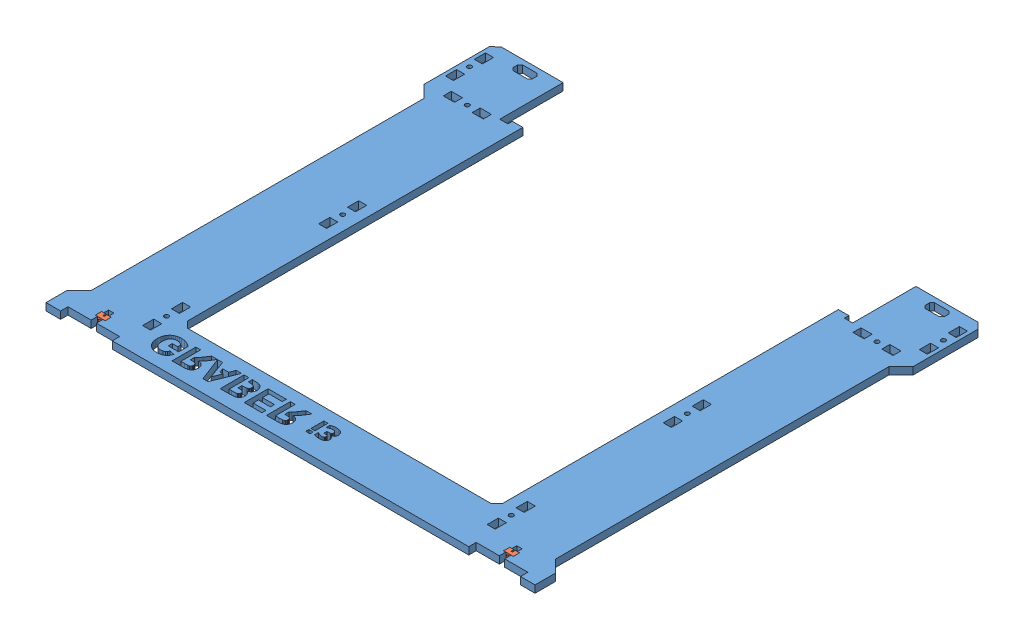
SolidWorks assembly Assembly Frame, configuration Valor predeterminado. Lengths in mm.
Overall size (402.95 7.94 370).
7 component instances, 3 part files, 9 mates.
Components (placement in the parent):
- Frame-1: Frame [Valor predeterminado] at (-231.8711 0 -298.6856) x (1 0 0) z (0 -1 0) size (402.95 370 6)
- Assembly m3-nut-adapter + Nut DIN 934 - M3-1: Assembly m3-nut-adapter + Nut DIN 934 - M3 [Valor predeterminado] at (-168.175 -3 101.0482) x (1 0 0) z (0 0 -1) size (8.25 7.94 5.1)
  - m3-nut-adapter-1: m3-nut-adapter [Valor predeterminado] at origin size (8 6 5.1)
  - Nut DIN 934 - M3-1: Nut DIN 934 - M3 [Valor predeterminado] at (0 0 3.9) x (0 0 1) z (-0.866025 -0.5 0) size (2.4 5.5 6.35)
- Assembly m3-nut-adapter + Nut DIN 934 - M3-2: Assembly m3-nut-adapter + Nut DIN 934 - M3 [Valor predeterminado] at (168.175 -3 101.0482) x (1 0 0) z (0 0 -1) size (8.25 7.94 5.1)
  - m3-nut-adapter-1: m3-nut-adapter [Valor predeterminado] at origin size (8 6 5.1)
  - Nut DIN 934 - M3-1: Nut DIN 934 - M3 [Valor predeterminado] at (0 0 3.9) x (0 0 1) z (-0.866025 -0.5 0) size (2.4 5.5 6.35)
Mates (geometry in assembly coordinates):
- Coincidente1: coincident: plane of assembly through (0 0 0) normal (0 1 0); plane of Frame-1 through (-231.8711 0 -298.6856) normal (0 1 0); plane of assembly
- Simétrico1: symmetric: plane of assembly; plane of assembly; plane of Frame-1 through (191.4749 -6 -189.0517) normal (1 0 0); plane of Frame-1 through (-191.4749 -6 85.4482) normal (-1 0 0); plane of assembly
- Coincidente3: coincident: plane of assembly; plane of assembly; plane of Frame-1 through (-231.8711 -6 -298.6856) normal (0 -1 0); plane of Assembly m3-nut-adapter + Nut DIN 934 - M3-1/m3-nut-adapter-1 through (-172.175 -6 95.9482) normal (0 -1 0)
- Coincidente4: coincident: plane of assembly; plane of assembly; plane of Frame-1 through (-164.175 -6 95.9482) normal (-1 0 0); plane of Assembly m3-nut-adapter + Nut DIN 934 - M3-1/m3-nut-adapter-1 through (-164.175 -6 95.9482) normal (1 0 0)
- Coincidente5: coincident: plane of assembly; plane of assembly; plane of Frame-1 through (-164.175 -6 101.0482) normal (0 0 -1); plane of Assembly m3-nut-adapter + Nut DIN 934 - M3-1/m3-nut-adapter-1 through (-168.175 -3 101.0482) normal (0 0 1)
- Coincidente6: coincident: plane of assembly; plane of assembly; plane of Frame-1 through (-231.8711 -6 -298.6856) normal (0 -1 0); plane of Assembly m3-nut-adapter + Nut DIN 934 - M3-2/m3-nut-adapter-1 through (164.175 -6 95.9482) normal (0 -1 0)
- Coincidente7: coincident: plane of assembly; plane of assembly; plane of Frame-1 through (164.175 -6 101.0482) normal (1 0 0); plane of Assembly m3-nut-adapter + Nut DIN 934 - M3-2/m3-nut-adapter-1 through (164.175 -6 95.9482) normal (-1 0 0)
- Coincidente8: coincident: plane of assembly; plane of assembly; plane of Frame-1 through (165.975 -6 101.0482) normal (0 0 -1); plane of Assembly m3-nut-adapter + Nut DIN 934 - M3-2/m3-nut-adapter-1 through (168.175 -3 101.0482) normal (0 0 1)
- Simétrico2: symmetric: plane of assembly; plane of assembly; plane of Frame-1 through (138.675 -6 -89.0425) normal (0 0 1); plane of Frame-1 through (145.275 -6 89.0425) normal (0 0 -1); plane of assembly
